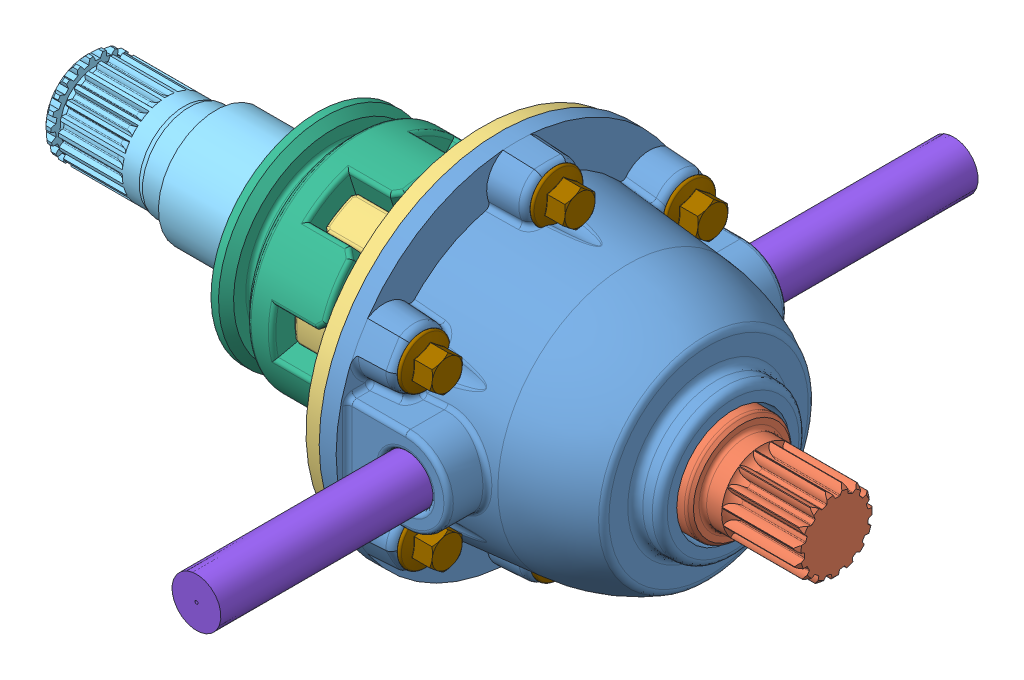
SolidWorks assembly Assem1, configuration Default. Lengths in mm.
Overall size (199.29 128.41 201.22).
15 component instances, 9 part files, 39 mates.
Components (placement in the parent):
- Part2-1: Part2 [Default] at origin size (62 96 96)
- Part5-gear2-1: Part5-gear2 [Default] at (47.65 0 0) x (-1 0 0) z (0 0.238751 0.971081) size (56.76 57.78 58.21)
- part3-2: part3 [Default] at (3.5 0 0) x (-1 0 0) z (0 -0.866025 -0.5) size (36 94 94)
- Part4-gear-original-1: Part4-gear-original [Default] at (-4.201 0 0) x (1 0 0) z (0 -0.778578 -0.627548) size (19.76 57.96 58.21)
- part4-1: part4 [Default] at (6.6553 0 0) x (-1 0 0) z (0 -0.329604 -0.944119) size (116.5 33.5 33.5)
- Part1-1: Part1 [Default] at (-31.5 0 0) x (0 0.866082 -0.499902) z (0 -0.499902 -0.866082) size (58 32.06 58)
- part6-washer-1: part6-washer [Default] at (51 0 0) x (0 0 1) z (-1 0 0) size (44 44 3.35)
- straight miter gear_iso-1: straight miter gear_iso [ISO - Straight miter gear 2.75M12T 20PA 12FW ---12O13H100MD0.8N] at (20 0 20) x (0 0 -1) z (-0.399778 0.916612 0) size (93.18 36.5 36.5)
- straight miter gear_iso-2: straight miter gear_iso [ISO - Straight miter gear 2.75M12T 20PA 12FW ---12O13H100MD0.8N] at (20 0 -20) x (0 0 1) z (-0.365406 -0.930848 0) size (93.18 36.5 36.5)
- hex flange bolt small_iso-1: hex flange bolt small_iso [ISO 4162 - M6 x 20 x 20-N] at (21.3 20.375 35.2905) x (-1 0 0) z (0 0.924225 0.381849) size (26.8 13.6 13.6)
- hex flange bolt small_iso-2: hex flange bolt small_iso [ISO 4162 - M6 x 20 x 20-N] at (21.3 40.75 0) x (-1 0 0) z (0 0.924225 0.381849) size (26.8 13.6 13.6)
- hex flange bolt small_iso-7: hex flange bolt small_iso [ISO 4162 - M6 x 20 x 20-N] at (21.3 20.375 -35.2905) x (-1 0 0) z (0 0.924225 0.381849) size (26.8 13.6 13.6)
- hex flange bolt small_iso-8: hex flange bolt small_iso [ISO 4162 - M6 x 20 x 20-N] at (21.3 -20.375 -35.2905) x (-1 0 0) z (0 0.924225 0.381849) size (26.8 13.6 13.6)
- hex flange bolt small_iso-9: hex flange bolt small_iso [ISO 4162 - M6 x 20 x 20-N] at (21.3 -40.75 0) x (-1 0 0) z (0 0.924225 0.381849) size (26.8 13.6 13.6)
- hex flange bolt small_iso-10: hex flange bolt small_iso [ISO 4162 - M6 x 20 x 20-N] at (21.3 -20.375 35.2905) x (-1 0 0) z (0 0.924225 0.381849) size (26.8 13.6 13.6)
Mates (geometry in assembly coordinates):
- Concentric1: concentric aligned: cylinder of Part2-1 through (-903.846 0 0) axis (-1 0 0) radius 19.5; cylinder of Part5-gear2-1 through (52.449 0 0) axis (-1 0 0) radius 14
- Parallel1: parallel anti-aligned: plane of Part2-1 through (51 25 0) normal (-1 0 0); plane of Part5-gear2-1 through (47.65 0 0) normal (1 0 0)
- Parallel9: parallel anti-aligned: plane of Part2-1 through (0 48 0) normal (-1 0 0); plane of part3-2 through (0 17 -29.4449) normal (1 0 0)
- Concentric17: concentric anti-aligned: cylinder of Part2-1 through (-903.846 0 0) axis (-1 0 0) radius 19.5; cylinder of part3-2 through (3.5 0 0) axis (1 0 0) radius 17
- Parallel11: parallel anti-aligned: cylinder of Part2-1 through (-115.5 40.75 0) axis (1 0 0) radius 3; cylinder of part3-2 through (8.5 40.75 0) axis (-1 0 0) radius 3
- Concentric21: concentric aligned: cylinder of part3-2 through (3.5 0 0) axis (1 0 0) radius 17; cylinder of Part4-gear-original-1 through (-9 0 0) axis (1 0 0) radius 14
- Coincident6: coincident anti-aligned: plane of part3-2 through (-9 7.25 -12.5574) normal (1 0 0); plane of Part4-gear-original-1 through (-9 0 0) normal (-1 0 0)
- Distance1: distance = 1 mm: plane of Part4-gear-original-1 through (5.6553 0 0) normal (1 0 0); plane of part4-1 through (6.6553 11.3294 -3.9553) normal (1 0 0)
- Concentric22: concentric aligned: cylinder of part3-2 through (3.5 0 0) axis (1 0 0) radius 47; cylinder of part4-1 through (6.6553 0 0) axis (1 0 0) radius 15.25
- Parallel17: parallel aligned: cylinder of Part4-gear-original-1 through (-11.3447 -7.3393 7.7862) axis (1 0 0) radius 3.2; cylinder of part4-1 through (-14.8447 8.8929 6.0398) axis (1 0 0) radius 3.2
- Concentric30: concentric aligned: cylinder of part4-1 through (6.6553 0 0) axis (1 0 0) radius 15.25; cylinder of Part1-1 through (-31.5 0 0) axis (1 0 0) radius 29
- Coincident8: coincident anti-aligned: plane of part3-2 through (-18.5 0 0) normal (-1 0 0); plane of Part1-1 through (-18.5 0 0) normal (1 0 0)
- Coincident9: coincident anti-aligned: plane of part3-2 through (-18.5 5.0289 -22.9556) normal (0 0.976835 0.213994); plane of Part1-1 through (-18.5 3.6379 -16.6062) normal (0 -0.976835 -0.213994)
- Concentric31: concentric anti-aligned: cylinder of Part5-gear2-1 through (52.449 0 0) axis (-1 0 0) radius 14; cylinder of part6-washer-1 through (47.65 0 0) axis (1 0 0) radius 14
- Coincident10: coincident anti-aligned: plane of Part5-gear2-1 through (47.65 0 0) normal (1 0 0); plane of part6-washer-1 through (47.65 0 0) normal (-1 0 0)
- Coincident11: coincident anti-aligned: plane of Part2-1 through (51 25 0) normal (-1 0 0); plane of part6-washer-1 through (51 0 0) normal (1 0 0)
- Concentric32: concentric anti-aligned: cylinder of Part2-1 through (20 0 -48.002) axis (0 0 1) radius 6.5; cylinder of straight miter gear_iso-1 through (20 0 100.6116) axis (0 0 -1) radius 6.5
- Coincident12: coincident anti-aligned: plane of Part2-1 through (20 0 20) normal (0 0 -1); plane of straight miter gear_iso-1 through (20 0 20) normal (0 0 1)
- GearMate1: gear = 13 : 12 mm: circle of straight miter gear_iso-1; circle of Part5-gear2-1
- Concentric34: concentric aligned: cylinder of Part2-1 through (20 0 -48.002) axis (0 0 1) radius 6.5; cylinder of straight miter gear_iso-2 through (20 0 -100.6116) axis (0 0 1) radius 6.5
- Coincident15: coincident anti-aligned: plane of Part2-1 through (20 0 -20) normal (0 0 1); plane of straight miter gear_iso-2 through (20 0 -20) normal (0 0 -1)
- GearMate3: gear = 12 : 13 mm: circle of Part5-gear2-1; circle of straight miter gear_iso-2
- Coincident16: coincident anti-aligned: plane of Part2-1 through (0 48 0) normal (-1 0 0); plane of part3-2 through (0 17 -29.4449) normal (1 0 0)
- GearMate4: gear = 12 : 13 mm: circle of Part4-gear-original-1; circle of straight miter gear_iso-1
- Lock2: lock: unknown of Part4-gear-original-1; unknown of part4-1
- Concentric35: concentric anti-aligned: cylinder of Part2-1 through (-115.5 40.75 0) axis (1 0 0) radius 3; cylinder of part3-2 through (8.5 40.75 0) axis (-1 0 0) radius 3
- GearMate5: gear = 12 : 13 mm: circle of Part4-gear-original-1; circle of straight miter gear_iso-2
- Concentric37: concentric anti-aligned: cone of Part2-1 through (4.5 20.375 35.2905) axis (-1 0 0); cylinder of hex flange bolt small_iso-1 through (21.3 20.375 35.2905) axis (1 0 0) radius 3
- Coincident17: coincident anti-aligned: plane of Part2-1 through (14.5 10.1875 17.6453) normal (1 0 0); plane of hex flange bolt small_iso-1 through (14.5 18.6113 39.5593) normal (-1 0 0)
- Concentric38: concentric anti-aligned: cone of Part2-1 through (4.5 40.75 0) axis (-1 0 0); cylinder of hex flange bolt small_iso-2 through (21.3 40.75 0) axis (1 0 0) radius 3
- Coincident18: coincident anti-aligned: plane of Part2-1 through (14.5 20.375 0) normal (1 0 0); plane of hex flange bolt small_iso-2 through (14.5 38.9863 4.2688) normal (-1 0 0)
- Concentric43: concentric anti-aligned: cone of Part2-1 through (4.5 20.375 -35.2905) axis (-1 0 0); cylinder of hex flange bolt small_iso-7 through (21.3 20.375 -35.2905) axis (1 0 0) radius 3
- Coincident23: coincident anti-aligned: plane of Part2-1 through (14.5 10.1875 -17.6453) normal (1 0 0); plane of hex flange bolt small_iso-7 through (14.5 18.6113 -31.0217) normal (-1 0 0)
- Concentric44: concentric anti-aligned: cone of Part2-1 through (4.5 -20.375 -35.2905) axis (-1 0 0); cylinder of hex flange bolt small_iso-8 through (21.3 -20.375 -35.2905) axis (1 0 0) radius 3
- Coincident24: coincident anti-aligned: plane of Part2-1 through (14.5 -10.1875 -17.6453) normal (1 0 0); plane of hex flange bolt small_iso-8 through (14.5 -22.1387 -31.0217) normal (-1 0 0)
- Concentric45: concentric anti-aligned: cone of Part2-1 through (4.5 -40.75 0) axis (-1 0 0); cylinder of hex flange bolt small_iso-9 through (21.3 -40.75 0) axis (1 0 0) radius 3
- Coincident25: coincident anti-aligned: plane of Part2-1 through (14.5 -20.375 0) normal (1 0 0); plane of hex flange bolt small_iso-9 through (14.5 -42.5137 4.2688) normal (-1 0 0)
- Concentric46: concentric anti-aligned: cone of Part2-1 through (4.5 -20.375 35.2905) axis (-1 0 0); cylinder of hex flange bolt small_iso-10 through (21.3 -20.375 35.2905) axis (1 0 0) radius 3
- Coincident26: coincident anti-aligned: plane of Part2-1 through (14.5 -10.1875 17.6453) normal (1 0 0); plane of hex flange bolt small_iso-10 through (14.5 -22.1387 39.5593) normal (-1 0 0)
